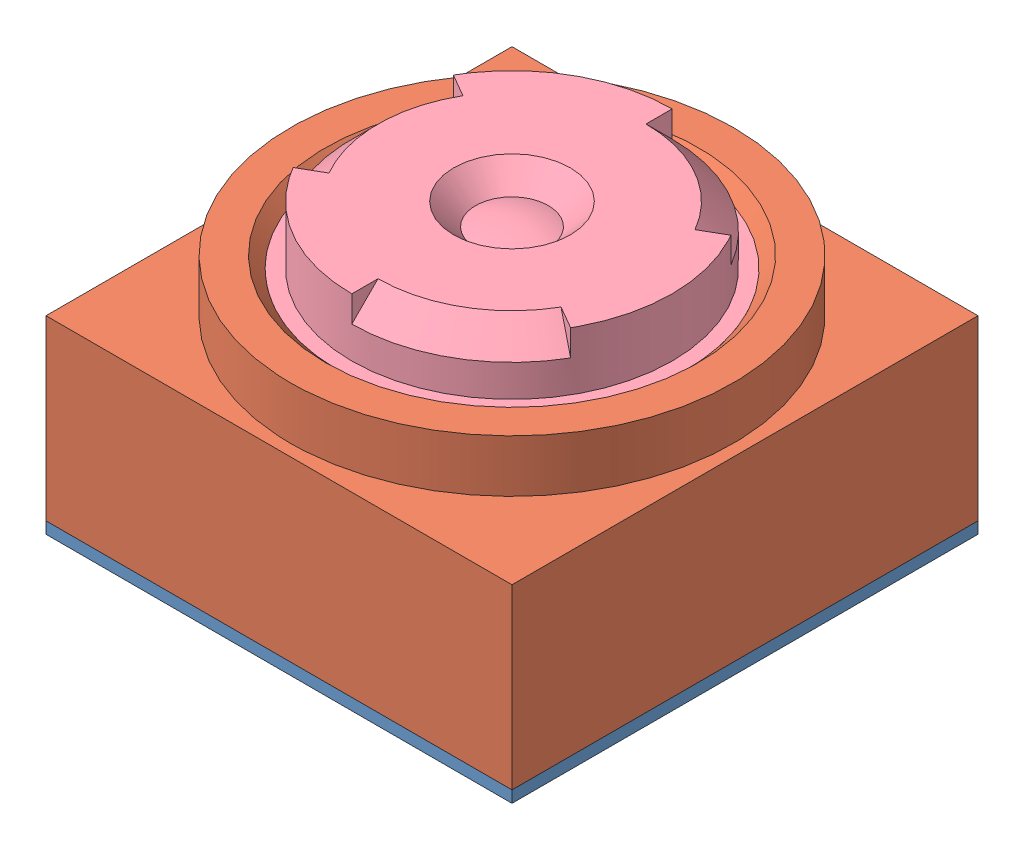
SolidWorks assembly RasPi_Camera_Mini, configuration FOV. Lengths in mm.
Overall size (8 4.95 8).
5 component instances, 4 part files, 0 mates.
Components (placement in the parent):
- OVA5647-2: OVA5647 [FOV] at (0.0315 -0.3517 0.0586) size (8 4.95 8)
  - OVA5647-1: OVA5647 [Standard] at (0.32 0 -0.175) size (8 0.68 8)
  - OVA5647_Housing-1: OVA5647_Housing [Standard] at origin size (8 3.95 8)
  - OVA5647_IR-Glas-1: OVA5647_IR-Glas [Standard] at (0 0.95 0) x (-1 0 0) z (0 0 1) size (6.3 0.35 6.3)
  - OVA5647_Lens-1: OVA5647_Lens [FOV] at (0 3.95 0) size (6 3.35 6)
